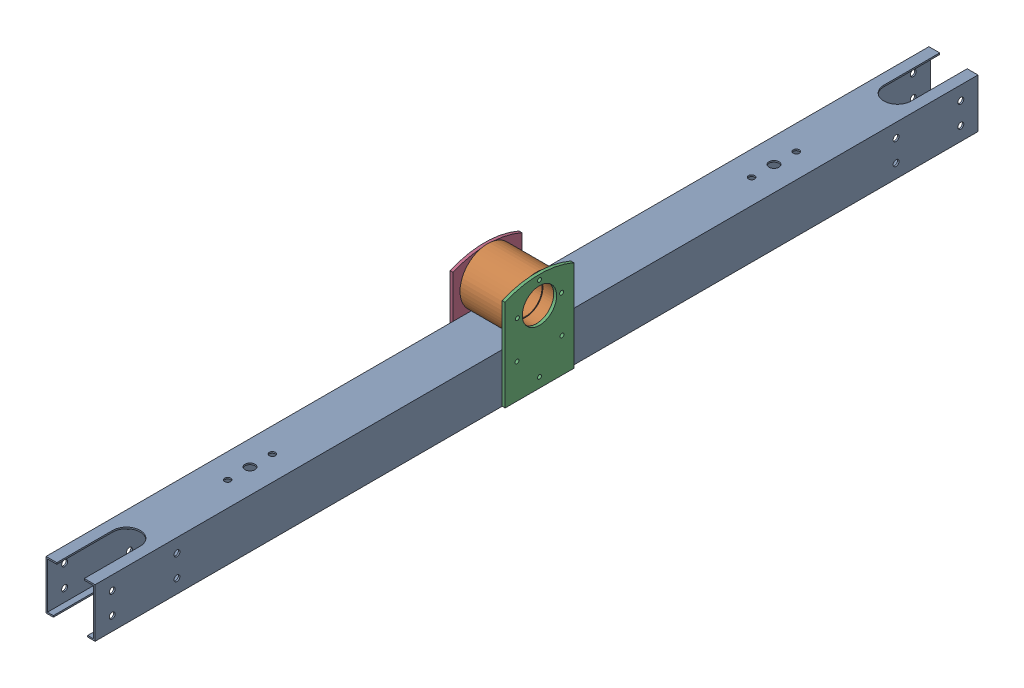
SolidWorks assembly v2joint_2-chassis-rocker, configuration Default. Lengths in mm.
Overall size (56 101 900).
4 component instances, 3 part files, 8 mates.
Components (placement in the parent):
- v2rocker1-1: v2rocker1 [Default] at (367.5021 494.6728 207.1881) size (50 50 900)
- v2housing - Copy-3: v2housing - Copy [Default] at (392.5021 519.6728 657.1881) x (0 0 1) z (-1 0 0) size (56 51 50)
- v2plate1-8: v2plate1 [Default] at (395.5021 522.1728 657.1881) x (0 0 1) z (-1 0 0) size (70 100.58 3)
- v2plate1-9: v2plate1 [Default] at (342.5021 522.1728 657.1881) x (0 0 1) z (-1 0 0) size (70 100.58 3)
Mates (geometry in assembly coordinates):
- Coincident1: coincident anti-aligned: plane of v2rocker1-1 through (342.5021 519.6728 1107.1881) normal (0 1 0); plane of housing - Copy-3 through (342.5021 519.6728 641.2194) normal (0 -1 0)
- Coincident2: coincident aligned: plane of v2rocker1-1 through (392.5021 519.6728 1107.1881) normal (1 0 0); plane of housing - Copy-3 through (392.5021 542.6728 657.1881) normal (1 0 0)
- Coincident3: coincident anti-aligned: plane of v2rocker1-1 through (392.5021 519.6728 1107.1881) normal (1 0 0); plane of plate1-8 through (392.5021 522.1728 657.1881) normal (-1 0 0)
- Concentric1: concentric anti-aligned: circle of rocker1-1; circle of plate1-8
- Concentric4: concentric anti-aligned: circle of housing - Copy-3; circle of plate1-8
- Coincident8: coincident anti-aligned: plane of v2rocker1-1 through (342.5021 519.6728 1107.1881) normal (-1 0 0); plane of plate1-9 through (342.5021 522.1728 657.1881) normal (1 0 0)
- Concentric5: concentric anti-aligned: circle of rocker1-1; circle of plate1-9
- Concentric6: concentric anti-aligned: circle of housing - Copy-3; circle of plate1-9
